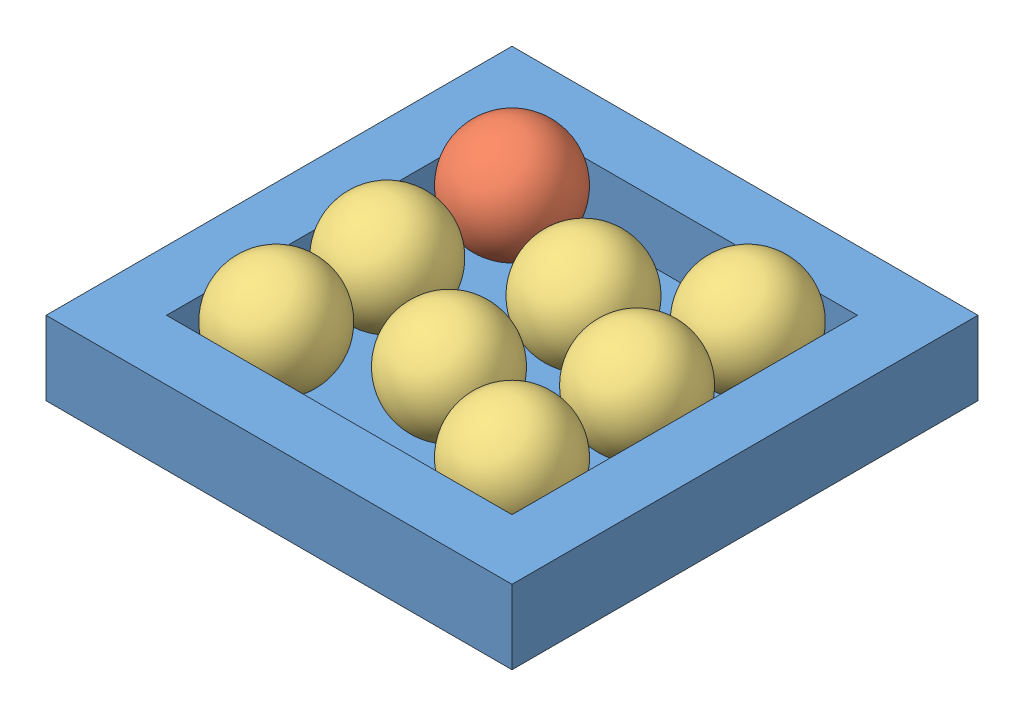
SolidWorks assembly Plateau_Cerises_rouges, configuration Défaut. Lengths in mm.
Overall size (170 65.97 170).
9 component instances, 3 part files, 18 mates.
Components (placement in the parent):
- Plateau-1: Plateau [Défaut] at (-100.5612 -27.0402 0) size (170 27 170)
- Cerise_rouge_2-1: Cerise_rouge_2 [Défaut] at (-58.5612 -22.0402 -128) size (40 40 40)
- Cerise_blanche_2-9: Cerise_blanche_2 [Défaut] at (-3.0437 -17.9881 -96.9141) x (0.913801 0.400708 -0.066344) z (-0.133805 0.451222 0.882324) size (40 40 40)
- Cerise_blanche_2-12: Cerise_blanche_2 [Défaut] at (28.0907 -22.0296 -41.9952) x (0.999469 0.032595 -0.000004) z (-0.000004 0.000242 1) size (40 40 40)
- Cerise_blanche_2-8: Cerise_blanche_2 [Défaut] at (-13.5903 -21.7458 -62.5519) x (0.999163 -0.040896 -0.0007) z (-0.006103 -0.165987 0.986109) size (40 40 40)
- Cerise_blanche_2-11: Cerise_blanche_2 [Défaut] at (29.7154 -21.9088 -87.8706) x (0.992862 0.113315 0.037203) z (-0.035595 -0.016185 0.999235) size (40 40 40)
- Cerise_blanche_2-7: Cerise_blanche_2 [Défaut] at (-57.9093 -22.0296 -41.9952) x (0.999469 0.032595 -0.000004) z (-0.000004 0.000242 1) size (40 40 40)
- Cerise_blanche_2-6: Cerise_blanche_2 [Défaut] at (-57.5719 -14.8239 -97.8402) x (0.998222 0.057229 0.01667) z (0.033266 -0.766923 0.640876) size (40 40 40)
- Cerise_blanche_2-10: Cerise_blanche_2 [Défaut] at (28.0907 -22.0296 -127.9952) x (0.999469 0.032595 -0.000004) z (-0.000004 0.000242 1) size (40 40 40)
Mates (geometry in assembly coordinates):
- Tangent1: tangent anti-aligned: plane of Plateau-1 through (-100.5612 -22.0402 -170) normal (0 1 0); sphere of Cerise_rouge_2-1
- Tangent2: tangent anti-aligned: plane of Plateau-1 through (-78.5612 -0.0402 -148) normal (0 0 1); sphere of Cerise_rouge_2-1
- Tangent3: tangent anti-aligned: plane of Plateau-1 through (-78.5612 -0.0402 -148) normal (1 0 0); sphere of Cerise_rouge_2-1
- Tangent4: tangent anti-aligned: plane of Plateau-1 through (-100.5612 -22.0402 -170) normal (0 1 0); sphere of Cerise_blanche_2-9
- Tangent6: tangent anti-aligned: plane of Plateau-1 through (-100.5612 -22.0402 -170) normal (0 1 0); sphere of Cerise_blanche_2-10
- Tangent7: tangent anti-aligned: plane of Plateau-1 through (-100.5612 -22.0402 -170) normal (0 1 0); sphere of Cerise_blanche_2-11
- Tangent8: tangent anti-aligned: plane of Plateau-1 through (-100.5612 -22.0402 -170) normal (0 1 0); sphere of Cerise_blanche_2-12
- Tangent9: tangent anti-aligned: plane of Plateau-1 through (-100.5612 -22.0402 -170) normal (0 1 0); sphere of Cerise_blanche_2-8
- Tangent10: tangent anti-aligned: plane of Plateau-1 through (-100.5612 -22.0402 -170) normal (0 1 0); sphere of Cerise_blanche_2-7
- Tangent11: tangent anti-aligned: plane of Plateau-1 through (-100.5612 -22.0402 -170) normal (0 1 0); sphere of Cerise_blanche_2-6
- Tangent12: tangent anti-aligned: plane of Plateau-1 through (-78.5612 -0.0402 -148) normal (1 0 0); sphere of Cerise_blanche_2-6
- Tangent13: tangent anti-aligned: plane of Plateau-1 through (-78.5612 -0.0402 -148) normal (1 0 0); sphere of Cerise_blanche_2-7
- Tangent14: tangent anti-aligned: plane of Plateau-1 through (-78.5612 -0.0402 -22) normal (0 0 -1); sphere of Cerise_blanche_2-7
- Tangent15: tangent anti-aligned: plane of Plateau-1 through (-78.5612 -0.0402 -22) normal (0 0 -1); sphere of Cerise_blanche_2-12
- Tangent16: tangent anti-aligned: plane of Plateau-1 through (47.4388 -0.0402 -148) normal (-1 0 0); sphere of Cerise_blanche_2-12
- Tangent17: tangent anti-aligned: plane of Plateau-1 through (-78.5612 -0.0402 -148) normal (0 0 1); sphere of Cerise_blanche_2-10
- Tangent18: tangent anti-aligned: plane of Plateau-1 through (47.4388 -0.0402 -148) normal (-1 0 0); sphere of Cerise_blanche_2-10
- Tangent19: tangent anti-aligned: plane of Plateau-1 through (47.4388 -0.0402 -148) normal (-1 0 0); sphere of Cerise_blanche_2-11
